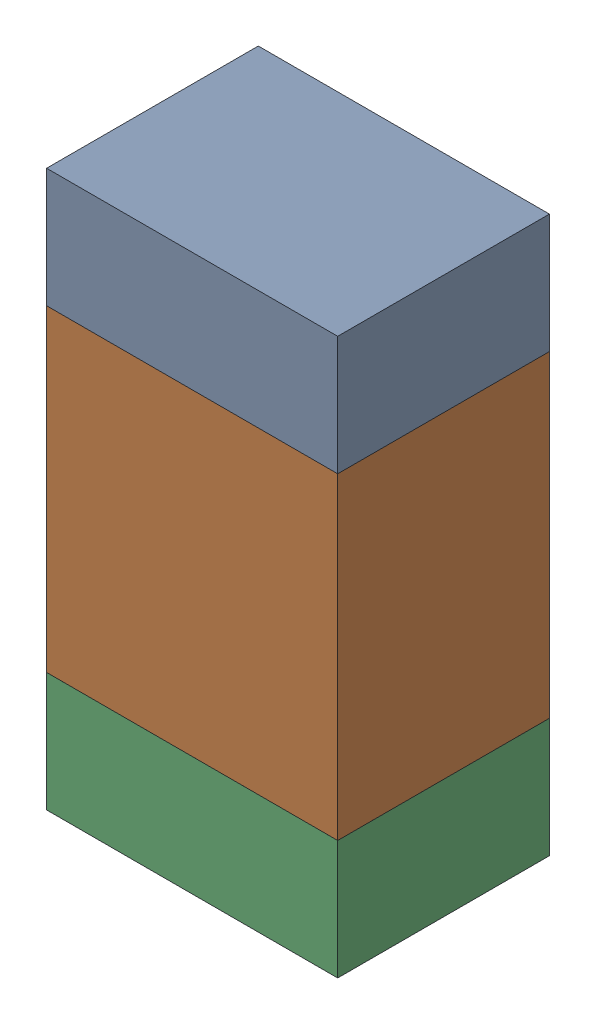
SolidWorks assembly R604_1PCB, configuration Default. Lengths in mm.
Overall size (0.55 1.05 0.4).
6 component instances, 2 part files, 0 mates.
Components (placement in the parent):
- 846483288-1: 846483288 [Default] at (100.5999 113.5124 -2.0638) size (0.55 0.22 0.4)
  - Extruded_12-1: Extruded_12 [Default] at origin size (0.55 0.22 0.4)
- 846483424-1: 846483424 [Default] at (100.5999 113.0999 -2.0638) size (0.55 0.6 0.4)
  - Extruded_13-1: Extruded_13 [Default] at origin size (0.55 0.6 0.4)
- 846483288-2: 846483288 [Default] at (100.5999 112.6874 -2.0638) size (0.55 0.22 0.4)
  - Extruded_12-1: Extruded_12 [Default] at origin size (0.55 0.22 0.4)
